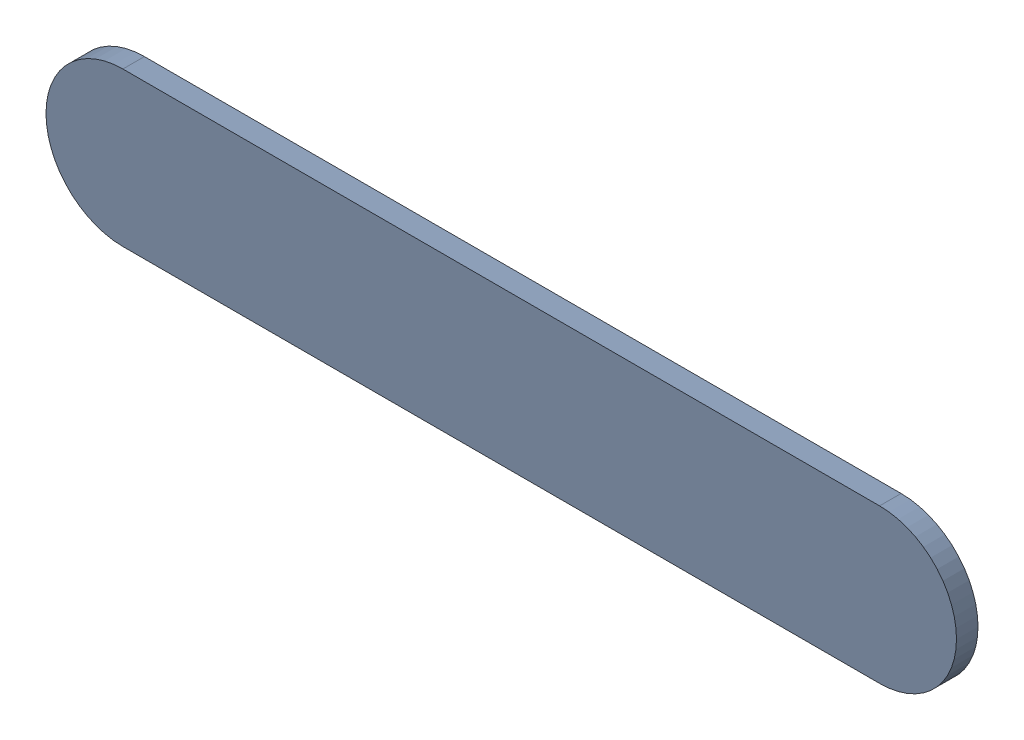
SolidWorks assembly Track (18.725mm,31.391mm)(19.975mm,31.391mm) on Top Layer, configuration Predeterminado. Lengths in mm.
Overall size (1.5 0.25 0.04).
2 component instances, 1 part files, 0 mates.
Components (placement in the parent):
- Track (18.725mm,31.391mm)(19.975mm,31.391mm) on Top Layer-1-1: Track (18.725mm,31.391mm)(19.975mm,31.391mm) on Top Layer-1 [Predeterminado] at (-68.317 -44.187 -0.0457) size (1.5 0.25 0.04)
  - Track (18.725mm,31.391mm)(19.975mm,31.391mm) on Top Layer-Part-1-1: Track (18.725mm,31.391mm)(19.975mm,31.391mm) on Top Layer-Part-1 [Predeterminado] at origin size (1.5 0.25 0.04)
